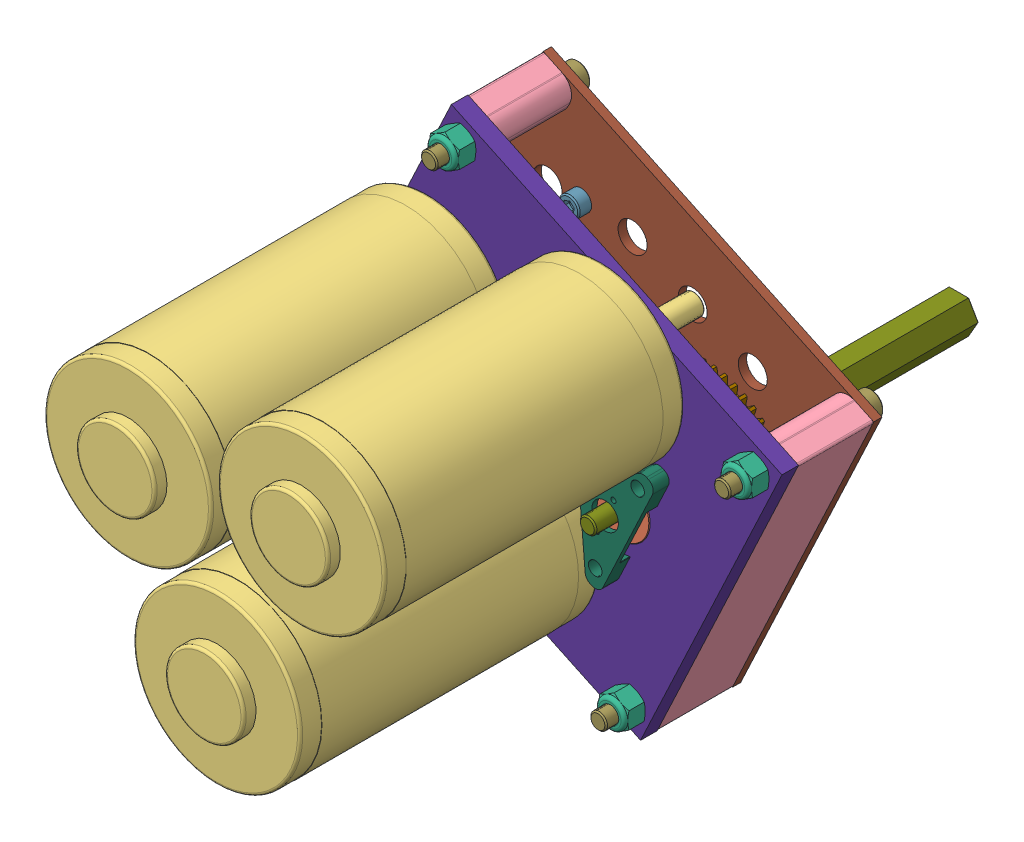
SolidWorks assembly 3CIM Gearbox with plate - AM14U, configuration Default. Lengths in mm.
Overall size (180.67 174.39 255.11).
30 component instances, 17 part files, 56 mates.
Components (placement in the parent):
- 500 E-klip-1: 500 E-klip [Default] at (16.1298 77.6456 -43.9601) x (-0.987566 -0.157207 0) z (0 0 1) size (19.07 20.96 1.27)
- FR6ZZ Bearing-1: FR6ZZ Bearing [Default] at (-13.0875 102.2889 -55.8473) x (0.991783 0.127931 0) z (0 0 -1) size (24.69 24.69 7.16)
- CIM Motor SW-1: CIM Motor SW [Default] at (-100.8929 87.6226 -3.2185) x (0 1 0) z (0 0 -1) size (64.01 64.01 154.94)
- ex-2508 Spacer-1: ex-2508 Spacer [Default] at (-92.2921 67.2369 -57.3713) x (0.425715 0.904857 0) z (0 0 1) size (127 14.35 28.75)
- CIM Motor SW-2: CIM Motor SW [Default] at (-101.4872 6.1263 -3.2185) x (-0.762709 0.646742 0) z (0 0 -1) size (64.01 64.01 154.94)
- Toughbox 14T Small Cluster-1: Toughbox 14T Small Cluster [Default] at (-21.1033 95.1629 -40.7851) x (-0.837052 0.547123 0) z (0 0 -1) size (20.03 20.32 15.25)
- 14-20 Nylock Nut_97135A210-1: 14-20 Nylock Nut_97135A210 [Default] at (19.7748 14.5119 -22.2685) x (1 0 0) z (0 -1 0) size (11.11 8.13 12.83)
- Toughbox 50T Large Cluster-1: Toughbox 50T Large Cluster [Default] at (-21.1033 95.1629 -40.7851) x (-0.055297 -0.99847 0) z (0 0 1) size (65.97 66.04 10.34)
- 10-32 Nylock Jam Nut_90633A411-1: 10-32 Nylock Jam Nut_90633A411 [Default] at (-34.2188 136.4219 -60.5463) x (0.976554 -0.215274 0) z (0.215274 0.976554 0) size (9.53 4.55 11)
- 14-20 Nylock Nut_97135A210-2: 14-20 Nylock Nut_97135A210 [Default] at (67.0932 115.0872 -22.2685) x (1 0 0) z (0 -1 0) size (11.11 8.13 12.83)
- 14-20 Nylock Nut_97135A210-3: 14-20 Nylock Nut_97135A210 [Default] at (-92.2921 67.2369 -22.2685) x (1 0 0) z (0 -1 0) size (11.11 8.13 12.83)
- ex-2508 Spacer-2: ex-2508 Spacer [Default] at (67.0932 115.0872 -57.3713) x (-0.425715 -0.904857 0) z (0 0 1) size (127 14.35 28.75)
- Toughbox 50T Output-1: Toughbox 50T Output [Default] at (16.1298 77.6456 -45.1793) x (1 0 0) z (0 0 -1) size (65.97 66.04 10.62)
- FR6ZZ Bearing-2: FR6ZZ Bearing [Default] at (-30.482 100.3659 -30.1425) x (-0.995778 -0.091798 0) z (0 0 1) size (24.69 24.69 7.16)
- FR8ZZ Hex Bearing-1: FR8ZZ Hex Bearing [Default] at (16.1298 77.6456 -63.2666) size (31.12 31.12 7.93)
- FR6ZZ Bearing-3: FR6ZZ Bearing [Default] at (7.2113 83.6032 -29.1773) x (-0.999955 -0.009486 0) z (0 0 1) size (24.69 24.69 7.16)
- 3CIM TB Special Shaft Plate-1: 3CIM TB Special Shaft Plate [Default] at (16.1298 77.6456 -57.3713) x (0.425715 0.904857 0) z (0 0 1) size (127 139.7 3.17)
- 10-32 Nylock Jam Nut_90633A411-2: 10-32 Nylock Jam Nut_90633A411 [Default] at (-61.2517 78.9634 -60.5463) x (0.733502 -0.679687 0) z (0.679687 0.733502 0) size (9.53 4.55 11)
- SHCS 14-20 x 2-1: SHCS 14-20 x 2 [Default] at (-44.9737 167.8122 -67.0995) x (0.867127 -0.498087 0) z (0.498087 0.867127 0) size (9.53 57.35 9.53)
- CIM Motor SW-3: CIM Motor SW [Default] at (-138.5887 47.3684 -3.2185) x (0.249226 0.968445 0) z (0 0 -1) size (64.01 64.01 154.94)
- SHCS 14-20 x 2-2: SHCS 14-20 x 2 [Default] at (67.0932 115.0872 -67.0995) x (1 0 0) z (0 1 0) size (9.53 57.35 9.53)
- TB Hex Shaft-1: TB Hex Shaft [Default] at (-63.6271 92.3312 -31.1331) x (-0.892349 -0.451347 0) z (-0.451347 0.892349 0) size (11 38.23 9.52)
- 10-32x0625_shcs_HX-SHCS 0.19-32x1.375x1-C-1: 10-32x0625_shcs_HX-SHCS 0.19-32x1.375x1-C [Default] at (-34.2188 136.4219 -52.5453) x (0 0 -1) z (0.658531 0.752554 0) size (20.7 7.94 7.94)
- Toughbox d29a-1: Toughbox d29a [Default] at (16.1298 77.6456 -22.2685) x (-0.904857 0.425715 0) z (0.425715 0.904857 0) size (19.05 6.1 50.8)
- SHCS 14-20 x 2-3: SHCS 14-20 x 2 [Default] at (19.7748 14.5119 -67.0995) x (1 0 0) z (0 1 0) size (9.53 57.35 9.53)
- 14-20 Nylock Nut_97135A210-4: 14-20 Nylock Nut_97135A210 [Default] at (-44.9737 167.8122 -22.2685) x (1 0 0) z (0 -1 0) size (11.11 8.13 12.83)
- TB Output Shaft Hex L-Base 2-1: TB Output Shaft Hex L-Base 2 [Default] at (20.8476 119.155 -54.5773) x (0.5 0.866025 0) z (-0.866025 0.5 0) size (14.66 148.64 12.7)
- 3CIM TB Special Motor Plate-1: 3CIM TB Special Motor Plate [Default] at (16.1298 77.6456 -57.1935) x (0.425715 0.904857 0) z (0 0 1) size (127 139.7 6.35)
- 10-32x0625_shcs_HX-SHCS 0.19-32x1.375x1-C-2: 10-32x0625_shcs_HX-SHCS 0.19-32x1.375x1-C [Default] at (-61.2517 78.9634 -52.5453) x (0 0 -1) z (1 0 0) size (20.7 7.94 7.94)
- SHCS 14-20 x 2-4: SHCS 14-20 x 2 [Default] at (-92.2921 67.2369 -67.0995) x (1 0 0) z (0 1 0) size (9.53 57.35 9.53)
Mates (geometry in assembly coordinates):
- Lock21: lock: unknown of 3CIM TB Special Shaft Plate-1; unknown of 10-32x0625_shcs_HX-SHCS 0.19-32x1.375x1-C-2
- Coincident1: coincident anti-aligned: plane of 3CIM TB Special Shaft Plate-1 through (-48.7708 178.3567 -57.3713) normal (0 0 1); circle of 10-32x0625_shcs_HX-SHCS 0.19-32x1.375x1-C-2
- Lock18: lock: unknown of 3CIM TB Special Shaft Plate-1; unknown of 10-32x0625_shcs_HX-SHCS 0.19-32x1.375x1-C-1
- Coincident3: coincident anti-aligned: plane of 3CIM TB Special Shaft Plate-1 through (-48.7708 178.3567 -57.3713) normal (0 0 1); circle of 10-32x0625_shcs_HX-SHCS 0.19-32x1.375x1-C-1
- Lock17: lock: unknown of 10-32 Nylock Jam Nut_90633A411-1; unknown of 10-32x0625_shcs_HX-SHCS 0.19-32x1.375x1-C-1
- Coincident4: coincident anti-aligned: plane of 10-32 Nylock Jam Nut_90633A411-1 through (-35.4027 131.0516 -60.5463) normal (0 0 1); plane of 3CIM TB Special Shaft Plate-1 through (-48.7708 178.3567 -60.5463) normal (0 0 -1)
- Lock19: lock: unknown of 10-32 Nylock Jam Nut_90633A411-2; unknown of 10-32x0625_shcs_HX-SHCS 0.19-32x1.375x1-C-2
- Coincident5: coincident anti-aligned: plane of 3CIM TB Special Shaft Plate-1 through (-48.7708 178.3567 -60.5463) normal (0 0 -1); plane of 10-32 Nylock Jam Nut_90633A411-2 through (-64.9895 74.9297 -60.5463) normal (0 0 1)
- Coincident6: coincident aligned: plane of 3CIM TB Special Shaft Plate-1 through (-48.7708 178.3567 -60.5463) normal (0 0 -1); circle of SHCS 14-20 x 2-1
- Lock9: lock: unknown of 3CIM TB Special Shaft Plate-1; unknown of SHCS 14-20 x 2-1
- Coincident7: coincident aligned: plane of 3CIM TB Special Shaft Plate-1 through (-48.7708 178.3567 -60.5463) normal (0 0 -1); circle of SHCS 14-20 x 2-4
- Lock15: lock: unknown of 3CIM TB Special Shaft Plate-1; unknown of SHCS 14-20 x 2-4
- Coincident8: coincident aligned: plane of 3CIM TB Special Shaft Plate-1 through (-48.7708 178.3567 -60.5463) normal (0 0 -1); circle of SHCS 14-20 x 2-3
- Lock13: lock: unknown of 3CIM TB Special Shaft Plate-1; unknown of SHCS 14-20 x 2-3
- Coincident9: coincident aligned: plane of 3CIM TB Special Shaft Plate-1 through (-48.7708 178.3567 -60.5463) normal (0 0 -1); circle of SHCS 14-20 x 2-2
- Lock11: lock: unknown of 3CIM TB Special Shaft Plate-1; unknown of SHCS 14-20 x 2-2
- Coincident10: coincident aligned: line of ex-2508 Spacer-2 through (77.3134 118.1948 -57.3713) axis (-0.425715 -0.904857 0); line of 3CIM TB Special Shaft Plate-1 through (77.6378 118.8843 -57.3713) axis (-0.425715 -0.904857 0)
- Coincident11: coincident aligned: line of ex-2508 Spacer-2 through (70.467 122.258 -57.3713) axis (0.904857 -0.425715 0); line of 3CIM TB Special Shaft Plate-1 through (-48.7708 178.3567 -57.3713) axis (0.904857 -0.425715 0)
- Coincident12: coincident aligned: line of ex-2508 Spacer-1 through (-48.0813 178.0323 -57.3713) axis (0.904857 -0.425715 0); line of 3CIM TB Special Shaft Plate-1 through (-48.7708 178.3567 -57.3713) axis (0.904857 -0.425715 0)
- Coincident13: coincident aligned: line of ex-2508 Spacer-1 through (-102.5122 64.1293 -57.3713) axis (0.425715 0.904857 0); line of 3CIM TB Special Shaft Plate-1 through (-102.8366 63.4398 -57.3713) axis (0.425715 0.904857 0)
- Coincident14: coincident anti-aligned: line of ex-2508 Spacer-1 through (-49.0952 177.6672 -28.6185) axis (-0.425715 -0.904857 0); line of 3CIM TB Special Motor Plate-1 through (-102.8366 63.4398 -28.6185) axis (0.425715 0.904857 0)
- Coincident15: coincident aligned: line of ex-2508 Spacer-1 through (-48.0813 178.0323 -28.6185) axis (0.904857 -0.425715 0); line of 3CIM TB Special Motor Plate-1 through (-48.7708 178.3567 -28.6185) axis (0.904857 -0.425715 0)
- Lock12: lock: unknown of 14-20 Nylock Nut_97135A210-2; unknown of SHCS 14-20 x 2-2
- Coincident16: coincident anti-aligned: plane of 14-20 Nylock Nut_97135A210-2 through (61.537 124.7109 -22.2685) normal (0 0 -1); plane of 3CIM TB Special Motor Plate-1 through (77.6378 118.8843 -22.2685) normal (0 0 1)
- Lock14: lock: unknown of 14-20 Nylock Nut_97135A210-1; unknown of SHCS 14-20 x 2-3
- Coincident17: coincident anti-aligned: plane of 14-20 Nylock Nut_97135A210-1 through (14.2186 24.1356 -22.2685) normal (0 0 -1); plane of 3CIM TB Special Motor Plate-1 through (77.6378 118.8843 -22.2685) normal (0 0 1)
- Lock16: lock: unknown of 14-20 Nylock Nut_97135A210-3; unknown of SHCS 14-20 x 2-4
- Coincident18: coincident anti-aligned: plane of 14-20 Nylock Nut_97135A210-3 through (-97.8483 76.8606 -22.2685) normal (0 0 -1); plane of 3CIM TB Special Motor Plate-1 through (77.6378 118.8843 -22.2685) normal (0 0 1)
- Lock10: lock: unknown of SHCS 14-20 x 2-1; unknown of 14-20 Nylock Nut_97135A210-4
- Coincident19: coincident anti-aligned: plane of 14-20 Nylock Nut_97135A210-4 through (-50.5299 177.4359 -22.2685) normal (0 0 -1); plane of 3CIM TB Special Motor Plate-1 through (77.6378 118.8843 -22.2685) normal (0 0 1)
- Coincident20: coincident anti-aligned: circle of FR8ZZ Hex Bearing-1; circle of 3CIM TB Special Shaft Plate-1
- Coincident21: coincident anti-aligned: circle of FR6ZZ Bearing-3; circle of 3CIM TB Special Motor Plate-1
- Lock2: lock: unknown of FR6ZZ Bearing-3; unknown of TB Output Shaft Hex L-Base 2-1
- Coincident24: coincident anti-aligned: circle of FR6ZZ Bearing-1; circle of 3CIM TB Special Shaft Plate-1
- Coincident26: coincident aligned: circle of FR6ZZ Bearing-2; circle of 3CIM TB Special Motor Plate-1
- Lock5: lock: unknown of FR6ZZ Bearing-1; unknown of TB Hex Shaft-1
- Coincident27: coincident aligned: plane of FR6ZZ Bearing-1 through (-21.1033 95.1629 -63.0101) normal (0 0 -1); plane of TB Hex Shaft-1 through (-21.1033 95.1629 -63.0101) normal (0 0 -1)
- Coincident28: coincident anti-aligned: plane of Toughbox 14T Small Cluster-1 through (-20.7992 100.6538 -40.7851) normal (0.451347 -0.892349 0); plane of TB Hex Shaft-1 through (-25.7064 98.1717 -31.1331) normal (-0.451347 0.892349 0)
- Coincident29: coincident aligned: plane of FR6ZZ Bearing-1 through (-21.1033 95.1629 -55.8473) normal (0 0 1); circle of Toughbox 14T Small Cluster-1
- Coincident32: coincident anti-aligned: plane of Toughbox 14T Small Cluster-1 through (-21.4074 89.6721 -40.7851) normal (-0.451347 0.892349 0); plane of TB Hex Shaft-1 through (-16.5001 92.1541 -31.1331) normal (0.451347 -0.892349 0)
- Coincident34: coincident anti-aligned: plane of Toughbox 14T Small Cluster-1 through (-16.196 97.645 -40.7851) normal (-0.547123 -0.837052 0); plane of TB Hex Shaft-1 through (-20.7992 100.6538 -31.1331) normal (0.547123 0.837052 0)
- Lock1: lock: unknown of Toughbox 50T Output-1; unknown of FR8ZZ Hex Bearing-1
- Lock3: lock: unknown of 500 E-klip-1; unknown of TB Output Shaft Hex L-Base 2-1
- Coincident41: coincident: line of Toughbox 50T Large Cluster-1 through (-21.4074 89.6721 -40.7851) axis (0.892349 0.451347 0); plane of TB Hex Shaft-1 through (-16.5001 92.1541 -31.1331) normal (0.451347 -0.892349 0)
- Coincident42: coincident: line of Toughbox 50T Large Cluster-1 through (-16.196 97.645 -40.7851) axis (-0.837052 0.547123 0); plane of TB Hex Shaft-1 through (-20.7992 100.6538 -31.1331) normal (0.547123 0.837052 0)
- Coincident43: coincident anti-aligned: plane of Toughbox 14T Small Cluster-1 through (-21.1033 95.1629 -40.7851) normal (0 0 1); plane of Toughbox 50T Large Cluster-1 through (-21.1033 95.1629 -40.7851) normal (0 0 -1)
- Lock23: lock: unknown of FR6ZZ Bearing-3; unknown of Toughbox d29a-1
- Lock24: lock: unknown of Toughbox d29a-1; unknown of 3CIM TB Special Motor Plate-1
- Coincident45: coincident anti-aligned: plane of Toughbox d29a-1 through (35.5617 96.574 -22.2685) normal (0 0 -1); plane of 3CIM TB Special Motor Plate-1 through (77.6378 118.8843 -22.2685) normal (0 0 1)
- Lock8: lock: unknown of CIM Motor SW-1; unknown of 3CIM TB Special Motor Plate-1
- Coincident46: coincident anti-aligned: plane of CIM Motor SW-1 through (8.4033 123.1826 -22.2685) normal (0 0 -1); plane of 3CIM TB Special Motor Plate-1 through (77.6378 118.8843 -22.2685) normal (0 0 1)
- Lock6: lock: unknown of CIM Motor SW-2; unknown of 3CIM TB Special Motor Plate-1
- Coincident47: coincident anti-aligned: plane of CIM Motor SW-2 through (-57.9226 112.4856 -22.2685) normal (0 0 -1); plane of 3CIM TB Special Motor Plate-1 through (77.6378 118.8843 -22.2685) normal (0 0 1)
- Lock22: lock: unknown of CIM Motor SW-3; unknown of 3CIM TB Special Motor Plate-1
- Coincident48: coincident anti-aligned: plane of CIM Motor SW-3 through (-23.8789 54.5669 -22.2685) normal (0 0 -1); plane of 3CIM TB Special Motor Plate-1 through (77.6378 118.8843 -22.2685) normal (0 0 1)
- Lock4: lock: unknown of FR8ZZ Hex Bearing-1; unknown of 3CIM TB Special Shaft Plate-1
